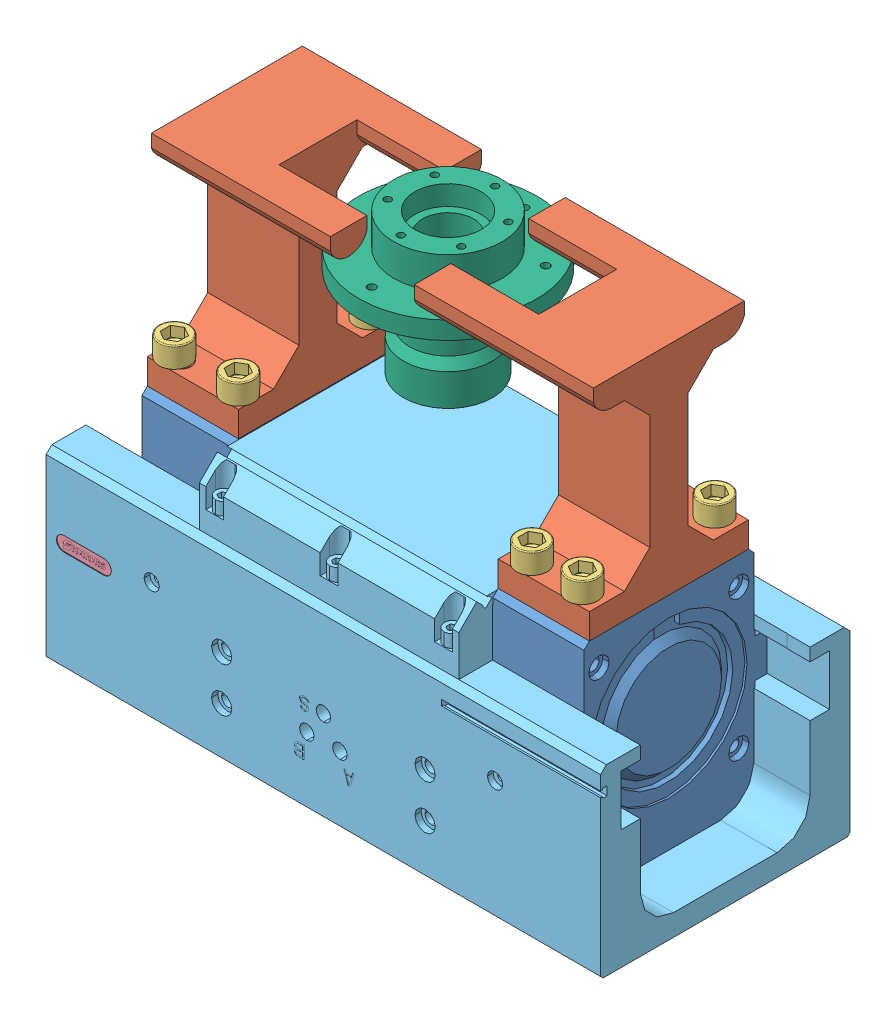
SolidWorks assembly SCHUNK_0302120_SPG_100_SDV_P__950ohne, configuration Default. Lengths in mm.
Overall size (436 366.6 196).
19 component instances, 7 part files, 15 mates.
Components (placement in the parent):
- Griffa_Dx-1: Griffa_Dx [Default] at (-40.4405 95.7023 19.6311) x (0 0 1) z (-1 0 0) size (154.2 344.41 176)
  - SCHUNK_0302120_SPG_100_SDV_P__950ohne_3-1: SCHUNK_0302120_SPG_100_SDV_P__950ohne_3 [Default] at (0 -15.2 87.35) size (154.2 173.7 174.7)
  - griffa-1: griffa [Default] at (45 226.7 138.85) x (-1 0 0) z (0 0 1) size (125.01 170.71 140.85)
  - socket head cap screw_iso-1: socket head cap screw_iso [ISO 4762 M16 x 25 - 25N] at (52 97.7 113.7) x (0 -1 0) z (0 0 1) size (41 24 24)
  - socket head cap screw_iso-2: socket head cap screw_iso [ISO 4762 M16 x 25 - 25N] at (52 97.7 164) x (0 -1 0) z (0 0 1) size (41 24 24)
  - socket head cap screw_iso-3: socket head cap screw_iso [ISO 4762 M16 x 25 - 25N] at (-52 97.7 113.7) x (0 -1 0) z (0 0 -1) size (41 24 24)
  - socket head cap screw_iso-4: socket head cap screw_iso [ISO 4762 M16 x 25 - 25N] at (-52 97.7 164) x (0 -1 0) z (0 0 -1) size (41 24 24)
- Griffa_Sx-1: Griffa_Sx [Default] at (-42.4405 95.7023 19.3811) x (0 0 -1) z (1 0 0) size (154.2 344.41 174.7)
  - SCHUNK_0302120_SPG_100_SDV_P__950ohne_3-1: SCHUNK_0302120_SPG_100_SDV_P__950ohne_3 [Default] at (0 -15.2 87.35) size (154.2 173.7 174.7)
  - griffa-1: griffa [Default] at (45 226.7 138.85) x (-1 0 0) z (0 0 1) size (125.01 170.71 140.85)
  - socket head cap screw_iso-1: socket head cap screw_iso [ISO 4762 M16 x 25 - 25N] at (-52 97.7 158.7) x (0 -1 0) z (0 0 1) size (41 24 24)
  - socket head cap screw_iso-2: socket head cap screw_iso [ISO 4762 M16 x 25 - 25N] at (-52 97.7 119) x (0 -1 0) z (0 0 1) size (41 24 24)
  - socket head cap screw_iso-3: socket head cap screw_iso [ISO 4762 M16 x 25 - 25N] at (52 97.7 158.7) x (0 -1 0) z (0 0 -1) size (41 24 24)
  - socket head cap screw_iso-4: socket head cap screw_iso [ISO 4762 M16 x 25 - 25N] at (52 97.7 119) x (0 -1 0) z (0 0 -1) size (41 24 24)
- Griffa_Base-1: Griffa_Base [Default] at (-41.4405 -34.1977 19.3811) size (436 191 196)
  - SCHUNK_0302120_SPG_100_SDV_P__950ohne_6-1: SCHUNK_0302120_SPG_100_SDV_P__950ohne_6 [Default] at (-188.35 86.7 97.3) x (-1 0 0) z (0 0 1) size (43 11 0.3)
  - SCHUNK_0302120_SPG_100_SDV_P__950ohne_8-1: SCHUNK_0302120_SPG_100_SDV_P__950ohne_8 [Default] at origin size (436 191 196)
- XSR201_lavorato-1: XSR201_lavorato [Default] at (-41.4405 267.4777 19.3811) x (0 1 0) z (-0.99865 0 -0.051938) size (110 140 140)
- Head Motor-1: Head Motor [Default] at (-41.4405 493.8564 154.6311) x (-1 0 0) z (0 0 1) size (370.59 268.41 410.5) (hidden)
Mates (geometry in assembly coordinates):
- Tangente5: tangent anti-aligned: cylinder of Griffa_Sx-1/griffa-1 through (60.5595 322.4023 64.3811) axis (1 0 0) radius 15; plane of XSR201_lavorato-1 through (-41.4405 307.4023 19.3811) normal (0 1 0)
- Tangente6: tangent anti-aligned: plane of Griffa_Sx-1/griffa-1 through (32.85 356.6 -45) normal (-1 0 0); cylinder of Head Motor-1 through (-14.9 448.4542 45.25) axis (0 -1 0) radius 47.75
- Concentrico13: concentric anti-aligned: cylinder of Griffa_Dx-1/griffa-1 through (-74.2905 322.4023 64.6311) axis (-1 0 0) radius 15; cylinder of Head Motor-1 through (-151.4425 322.4023 64.6311) axis (1 0 0) radius 17.5
- Tangente7: tangent: plane of Assieme2^SCHUNK_0302120_SPG_100_SDV_P__950ohne-1/griffa-1 through (-32.85 356.6 45.25) normal (1 0 0); cylinder of Head Motor-1 through (-14.9 448.4542 45.25) axis (0 -1 0) radius 47.75
- Parallelo8: parallel anti-aligned: plane of Assieme3^SCHUNK_0302120_SPG_100_SDV_P__950ohne-1/SCHUNK_0302120_SPG_100_SDV_P__950ohne_8-1 through (158.5595 156.8023 117.3811) normal (0 1 0); plane of XSR201_lavorato-1 through (-41.4405 293.4023 19.3811) normal (0 -1 0)
- Concentrico14: concentric aligned: cylinder of Assieme3^SCHUNK_0302120_SPG_100_SDV_P__950ohne-1/SCHUNK_0302120_SPG_100_SDV_P__950ohne_8-1 through (-41.4405 -26.1977 19.3811) axis (0 -1 0) radius 21.5; cylinder of XSR201_lavorato-1 through (-41.4405 267.4777 19.3811) axis (0 -1 0) radius 23.5
- Parallelo9: parallel anti-aligned: plane of Assieme3^SCHUNK_0302120_SPG_100_SDV_P__950ohne-1/SCHUNK_0302120_SPG_100_SDV_P__950ohne_8-1 through (158.5595 156.8023 117.3811) normal (0 1 0); plane of Head Motor-1 through (-55.2024 279.4564 -47.8689) normal (0 -1 0)
- Parallelo10: parallel aligned: plane of Assieme3^SCHUNK_0302120_SPG_100_SDV_P__950ohne-1/SCHUNK_0302120_SPG_100_SDV_P__950ohne_8-1 through (176.5595 -34.1977 19.3811) normal (1 0 0); plane of Head Motor-1 through (25.5595 322.4023 64.6311) normal (1 0 0)
- Coincidente23: coincident anti-aligned: plane of Griffa_Sx-1/SCHUNK_0302120_SPG_100_SDV_P__950ohne_3-1 through (60.5595 157.5523 -67.9689) normal (-1 0 0); plane of Assieme3^SCHUNK_0302120_SPG_100_SDV_P__950ohne-1/SCHUNK_0302120_SPG_100_SDV_P__950ohne_8-1 through (60.5595 157.8023 169.3811) normal (1 0 0)
- Coincidente24: coincident anti-aligned: plane of Griffa_Sx-1/SCHUNK_0302120_SPG_100_SDV_P__950ohne_3-1 through (132.2595 153.1596 86.1311) normal (0 0 1); plane of Assieme3^SCHUNK_0302120_SPG_100_SDV_P__950ohne-1/SCHUNK_0302120_SPG_100_SDV_P__950ohne_8-1 through (176.5595 60.7023 86.1311) normal (0 0 -1)
- Coincidente25: coincident anti-aligned: plane of Griffa_Sx-1/SCHUNK_0302120_SPG_100_SDV_P__950ohne_3-1 through (132.2595 -16.2977 60.1311) normal (0 -1 0); plane of Assieme3^SCHUNK_0302120_SPG_100_SDV_P__950ohne-1/SCHUNK_0302120_SPG_100_SDV_P__950ohne_8-1 through (176.5595 -16.2977 60.1311) normal (0 1 0)
- Coincidente26: coincident anti-aligned: plane of Griffa_Dx-1/SCHUNK_0302120_SPG_100_SDV_P__950ohne_3-1 through (-143.4405 157.5523 106.9811) normal (1 0 0); plane of Assieme3^SCHUNK_0302120_SPG_100_SDV_P__950ohne-1/SCHUNK_0302120_SPG_100_SDV_P__950ohne_8-1 through (-143.4405 110.8023 169.3811) normal (-1 0 0)
- Coincidente27: coincident anti-aligned: plane of Griffa_Dx-1/SCHUNK_0302120_SPG_100_SDV_P__950ohne_3-1 through (-215.1405 100.2523 86.3811) normal (0 0 1); plane of Assieme3^SCHUNK_0302120_SPG_100_SDV_P__950ohne-1/SCHUNK_0302120_SPG_100_SDV_P__950ohne_8-1 through (158.5595 148.2023 86.3811) normal (0 0 -1)
- Coincidente28: coincident anti-aligned: plane of Griffa_Dx-1/SCHUNK_0302120_SPG_100_SDV_P__950ohne_3-1 through (-215.1405 -16.2977 -21.1189) normal (0 -1 0); plane of Assieme3^SCHUNK_0302120_SPG_100_SDV_P__950ohne-1/SCHUNK_0302120_SPG_100_SDV_P__950ohne_8-1 through (176.5595 -16.2977 60.1311) normal (0 1 0)
- Coincidente29: coincident anti-aligned: plane of Griffa_Base-1 through (-41.4405 -34.1977 19.3811) normal (1 0 0); plane of Head Motor-1 through (-41.4405 493.8564 154.6311) normal (-1 0 0)
